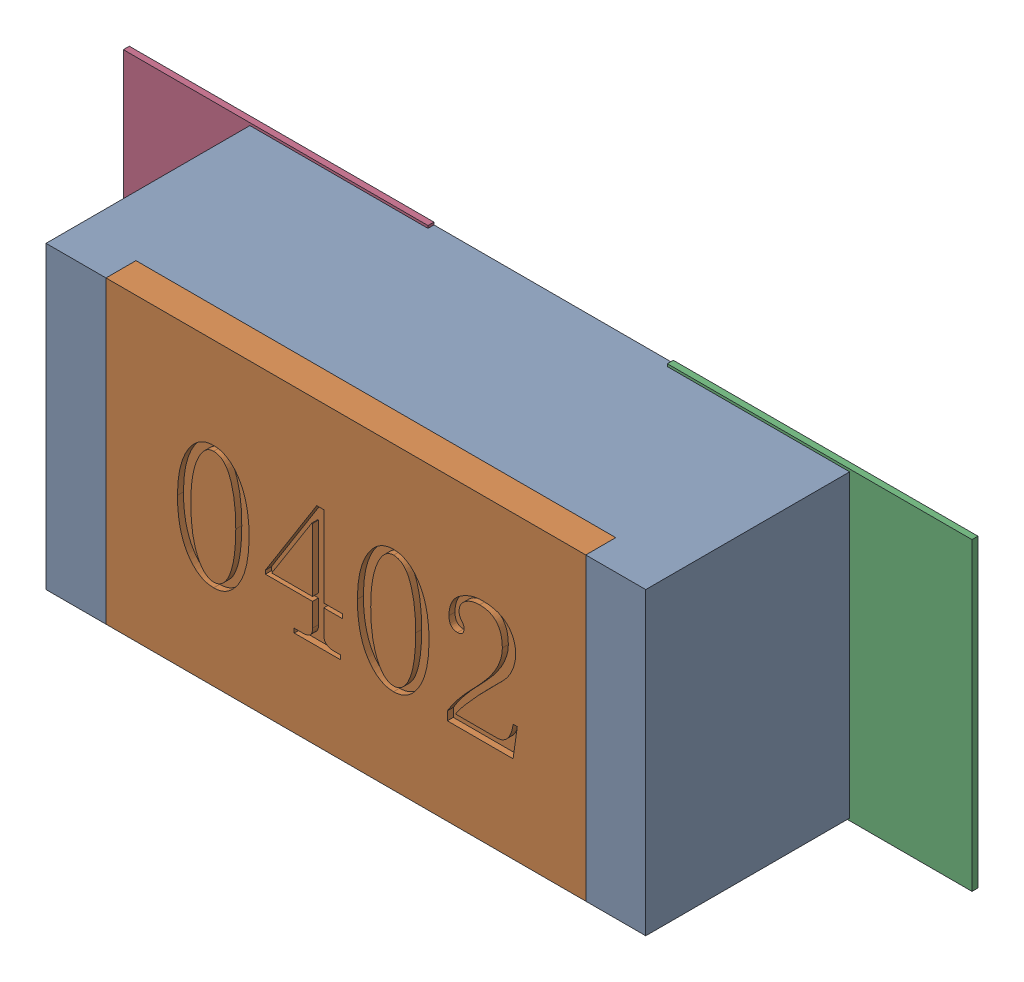
SolidWorks assembly R24, configuration Défaut. Lengths in mm.
Overall size (1.42 0.51 0.35).
5 component instances, 2 part files, 0 mates.
Components (placement in the parent):
- R0402-1: R0402 [Défaut] at (48.7957 -8.7056 0) x (1 0 0) z (0 0 1) size (1 0.5 0.35)
- 6504207776-1: 6504207776 [Défaut] at (49.2457 -8.7054 0) size (0.51 0.51 0.01)
  - Extruded-1: Extruded [Défaut] at origin size (0.51 0.51 0.01)
- 6504207776-2: 6504207776 [Défaut] at (48.3386 -8.7054 0) size (0.51 0.51 0.01)
  - Extruded-1: Extruded [Défaut] at origin size (0.51 0.51 0.01)
